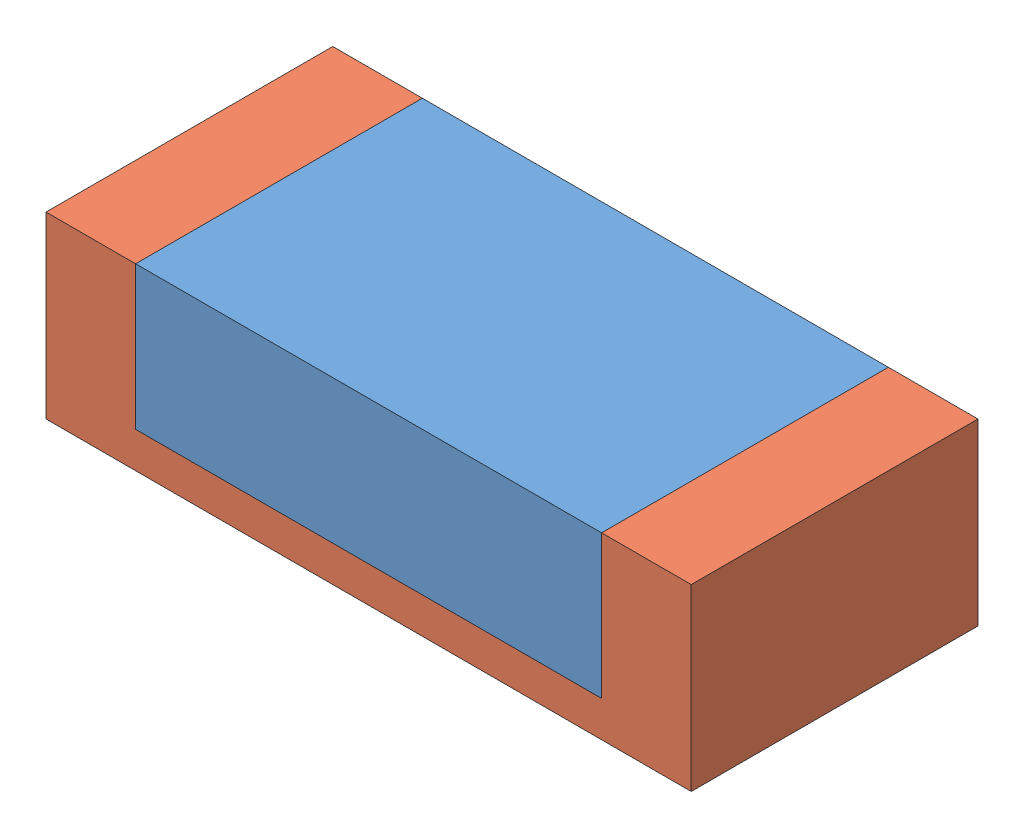
SolidWorks assembly black diod, configuration Default. Lengths in mm.
Overall size (1.8 0.5 0.8).
2 component instances, 2 part files, 4 mates.
Components (placement in the parent):
- black block diod-1: black block diod [Default] at (-0.3901 1.349 2.149) size (1.3 0.4 0.8)
- support diod2-1: support diod2 [Default] at (1.1599 1.249 1.349) size (1.8 0.5 0.8)
Mates (geometry in assembly coordinates):
- Coincident3: coincident aligned: line of support diod-2 through (0.9099 1.751 2.6252) axis (0 -1 0); line of black block diod-1 through (0.9099 1.351 2.6252) axis (0 -1 0)
- Coincident4: coincident anti-aligned: line of support diod-2 through (0.9099 0.951 2.6252) axis (-1 0 0); line of black block diod-1 through (-0.3901 0.951 2.6252) axis (1 0 0)
- Coincident5: coincident anti-aligned: line of black block diod-1 through (-0.3901 1.349 2.149) axis (1 0 0); line of support diod2-1 through (0.9099 1.349 2.149) axis (-1 0 0)
- Coincident6: coincident aligned: line of black block diod-1 through (0.9099 1.749 2.149) axis (0 -1 0); line of support diod2-1 through (0.9099 1.749 2.149) axis (0 -1 0)
